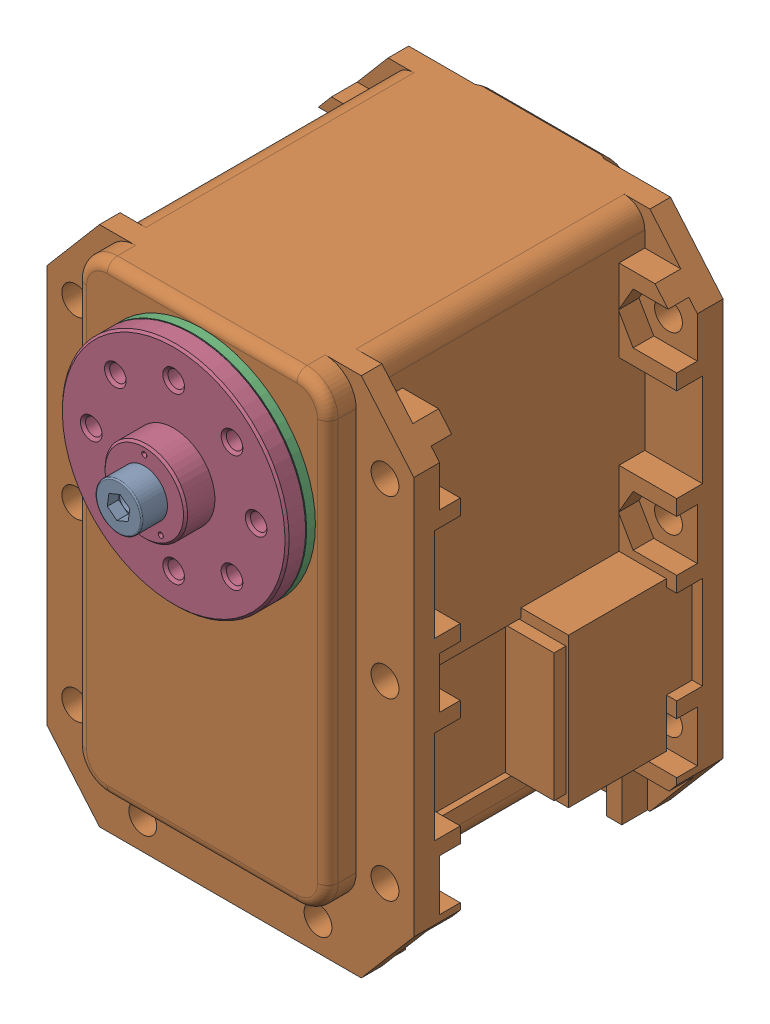
SolidWorks assembly MX-28(T)-3, configuration Default. Lengths in mm.
Overall size (35.6 54.13 45.1).
4 component instances, 4 part files, 0 mates.
Components (placement in the parent):
- WB_M2.5x8-1: WB_M2.5x8 [Default] at (0 0 25.85) x (0 0 -1) z (-0.991137 0.132843 0) size (10.5 4.5 4.5)
- dynamixel_x28series(Défaut)-1: dynamixel_x28series(Défaut) [Default] at origin size (35.6 50.71 41.85)
- trust_washer(Défaut)-1: trust_washer(Défaut) [Default] at (0 0 18.6) x (-0.666375 -0.745617 0) z (0.745617 -0.666375 0) size (22 0.85 22)
- HN07-N101(Défaut)-1: HN07-N101(Défaut) [Default] at (0 0 18.5) x (1 0 0) z (0 -1 0) size (22 5.85 22)
